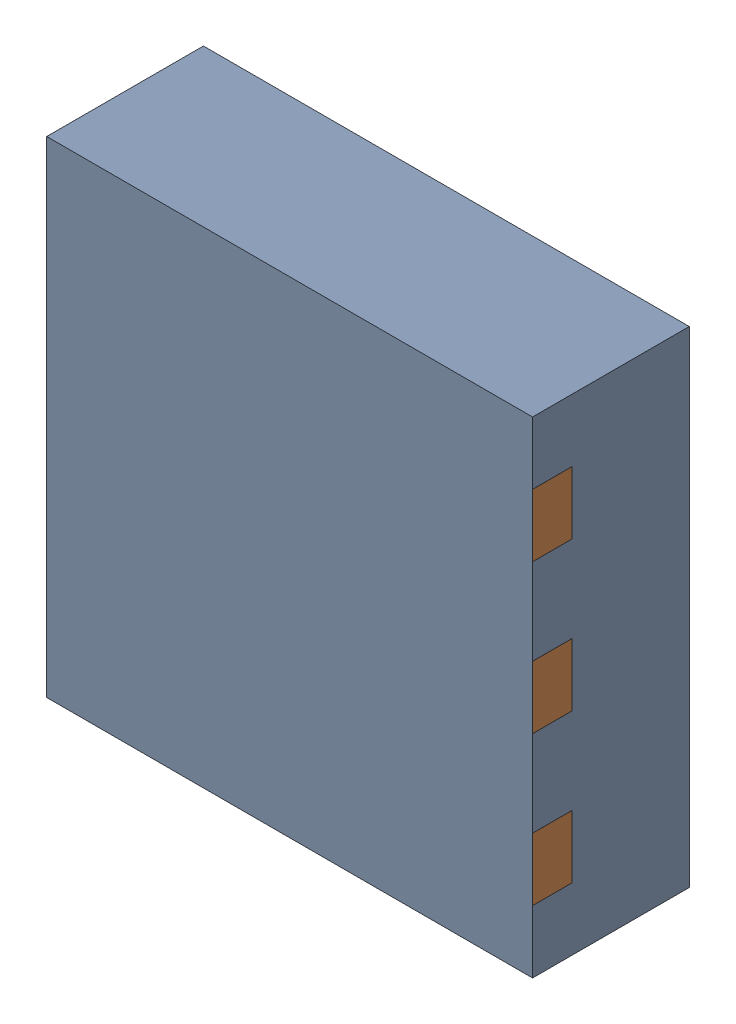
SolidWorks assembly U9, configuration Default. Lengths in mm.
Overall size (3.1 3.1 1).
3 component instances, 2 part files, 0 mates.
Components (placement in the parent):
- 1088884840-1: 1088884840 [Default] at (13.525 2.95 -2.644) size (3.1 3.1 1)
  - Extruded-16-1: Extruded-16 [Default] at origin size (3.1 3.1 1)
- DFN6-EPAD_3X3_P095-1: DFN6-EPAD_3X3_P095 [Default] at (13.5251 2.9501 -1.694) x (1 0 0) z (0 0 -1) size (3.1 3 0.8)
